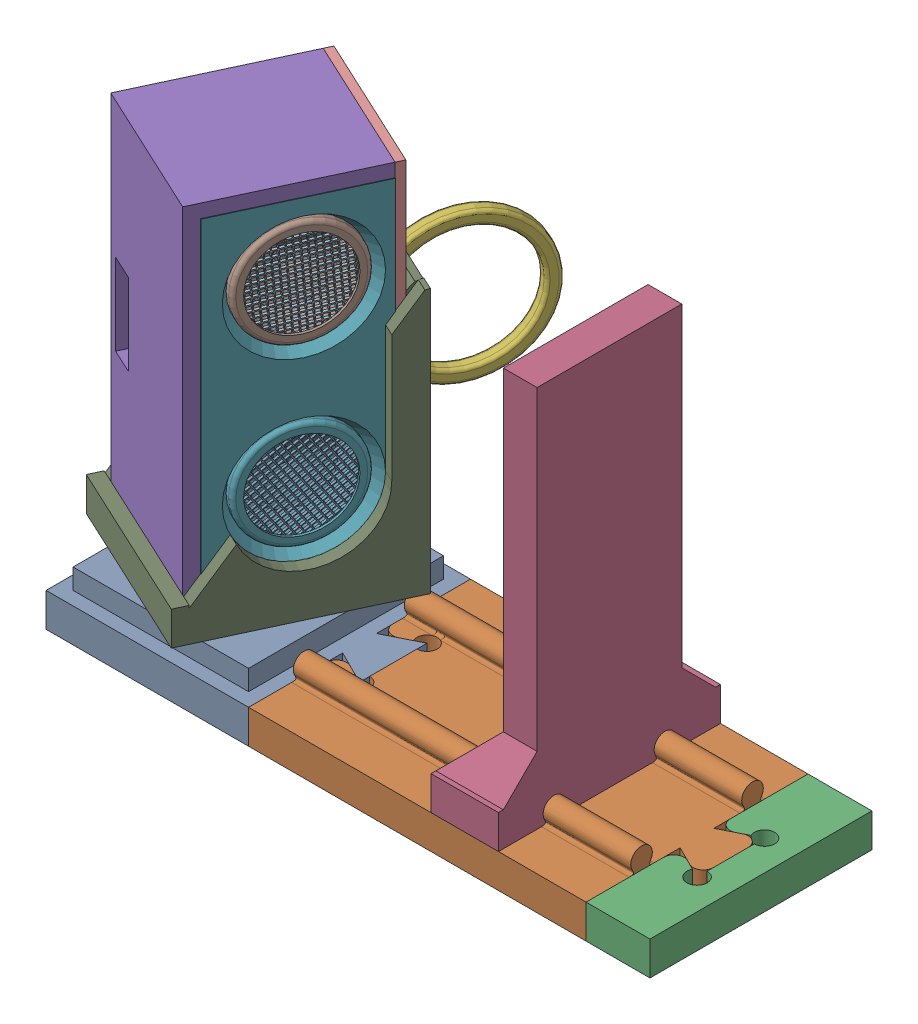
SolidWorks assembly 2.2.3.4_Medicion_Unidireccional_Distancia_Ultrasonido, configuration Predeterminado. Lengths in mm.
Overall size (114.02 83.27 83.27).
12 component instances, 10 part files, 2 mates.
Components (placement in the parent):
- 2.2.2.1_Mono_Guia_Lineal-1: 2.2.2.1_Mono_Guia_Lineal [Predeterminado] at (10.1898 -43.4745 33.6632) size (89.47 61.68 32.88)
  - 2.1.2.2.6_Base_Sujetador-1: 2.1.2.2.6_Base_Sujetador [Predeterminado] at (-44.4459 -5.7383 3.6115) x (-1 0 0) z (0 -1 0) size (35 32.88 8)
  - 2.1.2.2.7_Segmento_Riel-1: 2.1.2.2.7_Segmento_Riel [Predeterminado] at (-54.4459 -13.7383 3.6115) x (-1 0 0) z (0 -1 0) size (55.01 32.88 8.1)
  - 2.1.2.2.8_Segmento_Final_De_Riel-1: 2.1.2.2.8_Segmento_Final_De_Riel [Predeterminado] at (-54.4459 -13.7383 3.6115) x (-1 0 0) z (0 -1 0) size (9.47 32.88 5)
  - 2.1.2.2.9_Pared_De_Rebote-1: 2.1.2.2.9_Pared_De_Rebote [Predeterminado] at (-3.4196 -13.7383 3.6115) x (0 -1 0) z (1 0 0) size (56.68 32.88 10.01)
- 2.2.2.3_Caja_Ultrasonido-1: 2.2.2.3_Caja_Ultrasonido [Predeterminado] at (-69.7343 -12.876 -48.1277) x (0.419215 0.247516 0.873495) z (-0.884397 0.328775 0.331285) size (50.29 75.57 55.67)
  - 2.1.2.2.3_Cubierta_Posterior-1: 2.1.2.2.3_Cubierta_Posterior [Predeterminado] at (89.0125 -31.8608 0.2222) x (-0.247516 -0.911396 -0.328775) z (0.748898 0.035331 -0.661743) size (52.81 23.68 22)
  - 2.1.2.2.1_Manija-1: 2.1.2.2.1_Manija [Predeterminado] at (88.4905 -14.7597 21.6451) x (0.614726 -0.410011 0.673798) z (0.748898 0.035331 -0.661743) size (42.87 46.77 2.06)
  - 2.1.2.2.2_Cubierta_Frontal-1: 2.1.2.2.2_Cubierta_Frontal [Predeterminado] at (78.3032 -32.366 9.6851) x (0.247516 0.911396 0.328775) z (0.614726 -0.410011 0.673798) size (48.81 9.5 21.68)
  - HC-SR04.stp-1: HC-SR04.stp [Predeterminado] at (75.213 -29.0582 6.2192) x (-0.247516 -0.911396 -0.328775) z (0.748898 0.035331 -0.661743) size (45.62 20.4 15.39)
  - 2.1.2.2.5_Sujetador-1: 2.1.2.2.5_Sujetador [Predeterminado] at (82.4771 -55.9253 -8.4588) x (-0.748898 -0.035331 0.661743) z (-0.247516 -0.911396 -0.328775) size (26 28.88 48.33)
  - 2.1.2.2.4_Cubierta_Superior-1: 2.1.2.2.4_Cubierta_Superior [Predeterminado] at (65.6879 -24.0053 -3.9942) x (-0.247516 -0.911396 -0.328775) z (-0.614726 0.410011 -0.673798) size (52.81 22 15.2)
Mates (geometry in assembly coordinates):
- Concéntrica9: concentric aligned: cylinder of 2.2.2.1_Mono_Guia_Lineal-1/2.1.2.2.6_Base_Sujetador-1 through (-45.2561 -52.2128 28.1171) axis (0 1 0) radius 8; cylinder of Ensamblaje2^Ensamblaje1-1/2.1.2.2.5_Sujetador-1 through (-45.2561 -57.2128 28.1171) axis (0 1 0) radius 8
- Coincidente11: coincident aligned: plane of 2.2.2.1_Mono_Guia_Lineal-1/2.1.2.2.6_Base_Sujetador-1 through (-34.2561 -57.2128 37.2747) normal (0 -1 0); plane of Ensamblaje2^Ensamblaje1-1/2.1.2.2.5_Sujetador-1 through (-45.2561 -57.2128 28.1171) normal (0 -1 0)
